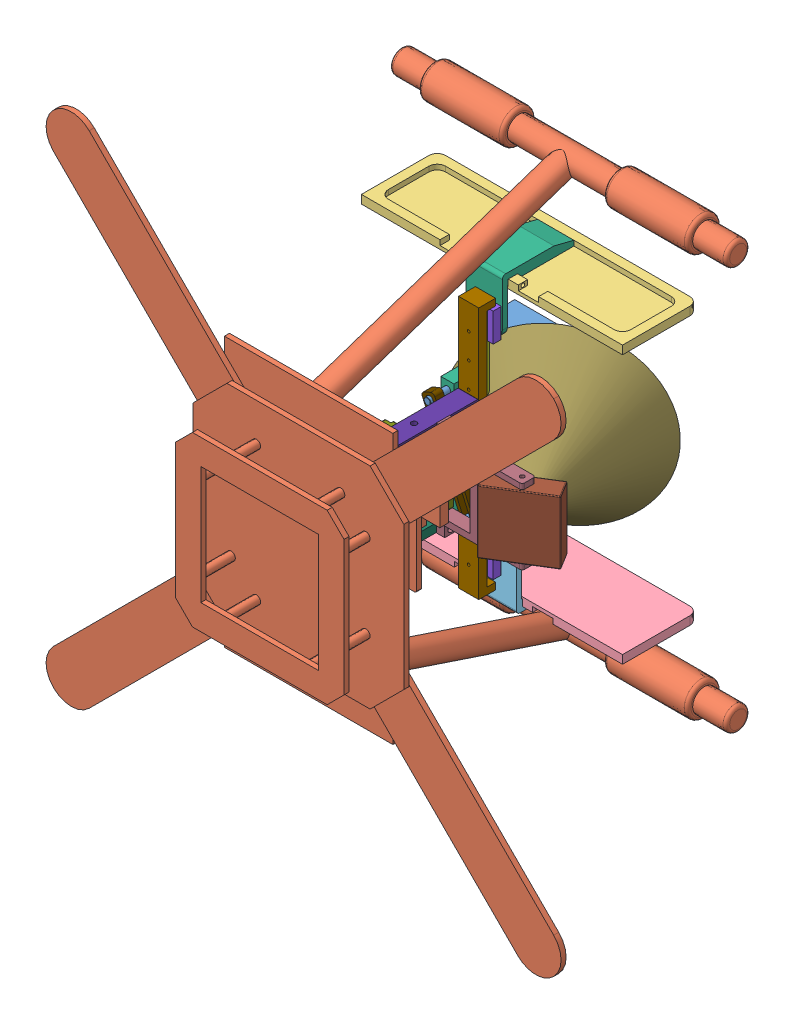
SolidWorks assembly 无人机抓取包裹, configuration 默认. Lengths in mm.
Overall size (305.77 305.77 197.93).
22 component instances, 20 part files, 59 mates.
Components (placement in the parent):
- 包裹-2: 包裹 [默认] at origin size (60 60 30)
- 无人机吊舱-2: 无人机吊舱 [默认] at (2.6457 0 120) size (305.77 305.77 194)
- 机械手-夹持板1-1: 机械手-夹持板1 [默认] at (0 77.0633 21) x (1 0 0) z (0 1 0) size (155 45 5)
- 机械手-夹持板2-2: 机械手-夹持板2 [默认] at (0 -77.0633 21) x (-1 0 0) z (0 -1 0) size (155 45 5)
- 导轨安装板-右侧-1: 导轨安装板-右侧 [默认] at (2.6457 -72.0633 46.5) x (0 1 0) z (0 0 -1) size (65 21.5 57.5)
- 导轨安装板-左侧-2: 导轨安装板-左侧 [默认] at (2.6457 72.0633 46.5) x (0 -1 0) z (0 0 -1) size (65 21.5 57.5)
- 导轨-1: 导轨 [默认] at (2.6457 0 55) x (0 -1 0) z (0 0 -1) size (140 5 4.8)
- 滑块-1: 滑块 [默认] at (2.6457 -52.0633 48.95) x (0 0 -1) z (0 -1 0) size (4.9 12 17)
- 滑块-2: 滑块 [默认] at (2.6457 69.0633 48.95) x (0 0 -1) z (0 -1 0) size (4.9 12 17)
- 导轨固定底板-1: 导轨固定底板 [默认] at (2.6457 0 60) x (0 -1 0) z (0 0 -1) size (150 12 10)
- 舵机转轴-2: 舵机转轴 [默认] at (2.6457 0 64) x (0.914342 0.404943 0) z (0 0 1) size (12 12 8.1)
- 摄像头-1: 摄像头 [默认] at (58.4666 0 85.8925) x (-0.850871 0 0.525374) z (-0.525374 0 -0.850871) size (36 37.5 17.5)
- 摄像头视角-1: 摄像头视角 [默认] at (49.5353 0 71.4277) x (0.277059 0.945502 -0.171071) z (0.8045 -0.325618 -0.496742) size (102.75 60 102.75)
- 摄像头固定支架-1: 摄像头固定支架 [默认] at (33.9457 0 85) x (0 1 0) z (0 0 -1) size (56.5 51 8)
- GB_FASTENER_SCREWS_SCHS M3X20-20-N-1: GB_FASTENER_SCREWS_SCHS M3X20-20-N [GB_FASTENER_SCREWS_SCHS M3X20-20-N] at (2.6457 0 63) x (0 0 1) z (-0.433867 0.900977 0) size (22.01 5.5 5.5)
- 连接板-1-1: 连接板-1 [默认] at (2.6457 -25.575 90) x (0 1 0) z (0 0 1) size (11 11.6 60)
- 单轴PWM舵机-1: 单轴PWM舵机 [默认] at (12.6457 0 78.1) x (-1 0 0) z (0 -1 0) size (57.5 45 20)
- 连接板-2-2: 连接板-2 [默认] at (2.6457 25.575 90) x (0 -1 0) z (0 0 1) size (11 11.6 60)
- 转动连杆-1: 转动连杆 [默认] at (2.6457 0 67) x (-0.914342 -0.404943 0) z (0 0 1) size (16 62.2 9)
- GB_FASTENER_SCREWS_HSHCS M4X25-N-1: GB_FASTENER_SCREWS_HSHCS M4X25-N [GB_FASTENER_SCREWS_HSHCS M4X25-N] at (13.7457 -25.0633 44.5) x (0 0 1) z (-0.946713 -0.322079 0) size (29 7 7)
- GB_FASTENER_SCREWS_HSHCS M4X25-N-2: GB_FASTENER_SCREWS_HSHCS M4X25-N [GB_FASTENER_SCREWS_HSHCS M4X25-N] at (-8.4543 25.0633 44.5) x (0 0 1) z (-0.907764 -0.419482 0) size (29 7 7)
- 舵机固定框-1: 舵机固定框 [默认] at (-7.3543 0 89.1) x (0 -1 0) z (0 0 1) size (46 54 5)
Mates (geometry in assembly coordinates):
- 宽度1: width: plane of assembly; plane of assembly; plane of assembly; plane of assembly; plane of 机械手-夹持板1-1 through (77.5 82.0633 43.5) normal (1 0 0); plane of 机械手-夹持板1-1 through (-77.5 82.0633 43.5) normal (-1 0 0); plane of 包裹-2 through (-30 -30 30) normal (-1 0 0); plane of 包裹-2 through (30 -30 30) normal (1 0 0)
- 宽度2: width: plane of assembly; plane of assembly; plane of assembly; plane of assembly; plane of 机械手-夹持板2-2 through (77.5 -82.0633 43.5) normal (1 0 0); plane of 机械手-夹持板2-2 through (-77.5 -82.0633 43.5) normal (-1 0 0); plane of 包裹-2 through (-30 -30 30) normal (-1 0 0); plane of 包裹-2 through (30 -30 30) normal (1 0 0)
- 平行1: parallel: plane of assembly; plane of assembly; plane of 包裹-2 through (30 -30 30) normal (0 -1 0); plane of 机械手-夹持板2-2 through (0 -77.0633 21) normal (0 1 0)
- 平行2: parallel: plane of assembly; plane of assembly; plane of 包裹-2 through (30 30 30) normal (0 1 0); plane of 机械手-夹持板1-1 through (0 77.0633 21) normal (0 -1 0)
- 重合1: coincident: plane of assembly; plane of assembly; plane of 机械手-夹持板2-2 through (0 -79.0633 21) normal (0 -1 0); plane of 导轨安装板-右侧-1 through (-2.3543 -79.0633 4) normal (0 1 0)
- 重合2: coincident: plane of assembly; plane of assembly; plane of 机械手-夹持板2-2 through (-77.5 -82.0633 43.5) normal (0 0 1); plane of 导轨安装板-右侧-1 through (2.6457 -72.0633 43.5) normal (0 0 -1)
- 重合3: coincident: plane of assembly; plane of assembly; plane of 机械手-夹持板1-1 through (0 79.0633 21) normal (0 1 0); plane of 导轨安装板-左侧-2 through (7.6457 79.0633 4) normal (0 -1 0)
- 重合4: coincident: plane of assembly; plane of assembly; plane of 机械手-夹持板1-1 through (77.5 82.0633 43.5) normal (0 0 1); plane of 导轨安装板-左侧-2 through (2.6457 72.0633 43.5) normal (0 0 -1)
- 宽度5: width: plane of assembly; plane of assembly; plane of assembly; plane of assembly; plane of 导轨-1 through (5.1457 -70 50.2) normal (1 0 0); plane of 导轨-1 through (0.1457 -70 50.2) normal (-1 0 0); plane of 滑块-1 through (5.1457 -52.0633 50.2) normal (-1 0 0); plane of 滑块-1 through (0.1457 -52.0633 51.4) normal (1 0 0)
- 重合5: coincident: plane of assembly; plane of assembly; plane of 导轨-1 through (2.6457 0 50.2) normal (0 0 -1); plane of 滑块-1 through (0.1457 -52.0633 50.2) normal (0 0 1)
- 宽度6: width: plane of assembly; plane of assembly; plane of assembly; plane of assembly; plane of 滑块-2 through (5.1457 69.0633 50.2) normal (-1 0 0); plane of 滑块-2 through (0.1457 69.0633 51.4) normal (1 0 0); plane of 导轨-1 through (5.1457 -70 50.2) normal (1 0 0); plane of 导轨-1 through (0.1457 -70 50.2) normal (-1 0 0)
- 重合6: coincident: plane of assembly; plane of assembly; plane of 导轨-1 through (2.6457 0 50.2) normal (0 0 -1); plane of 滑块-2 through (0.1457 69.0633 50.2) normal (0 0 1)
- 重合7: coincident: plane of assembly; plane of assembly; plane of 导轨安装板-左侧-2 through (2.6457 72.0633 46.5) normal (0 0 1); plane of 滑块-2 through (-3.3543 52.0633 46.5) normal (0 0 -1)
- 重合8: coincident: plane of assembly; plane of assembly; plane of 导轨安装板-左侧-2 through (7.6457 52.0633 43.5) normal (0 -1 0); plane of 滑块-2 through (2.6457 52.0633 48.95) normal (0 -1 0)
- 宽度7: width: plane of assembly; plane of assembly; plane of assembly; plane of assembly; plane of 导轨-1 through (5.1457 70 50.2) normal (0 1 0); plane of 导轨-1 through (5.1457 -70 50.2) normal (0 -1 0); plane of 包裹-2 through (30 -30 30) normal (0 -1 0); plane of 包裹-2 through (30 30 30) normal (0 1 0)
- 重合10: coincident: plane of assembly; plane of assembly; plane of 导轨安装板-右侧-1 through (2.6457 -72.0633 46.5) normal (0 0 1); plane of 滑块-1 through (-3.3543 -69.0633 46.5) normal (0 0 -1)
- 重合11: coincident: plane of assembly; plane of assembly; plane of 导轨-1 through (2.6457 0 55) normal (0 0 1); plane of 导轨固定底板-1 through (2.6457 0 55) normal (0 0 -1)
- 宽度8: width: plane of assembly; plane of assembly; plane of assembly; plane of assembly; plane of 导轨固定底板-1 through (-3.3543 71 50) normal (0 -1 0); plane of 导轨固定底板-1 through (-3.3543 -71 50) normal (0 1 0); plane of 导轨-1 through (5.1457 -70 50.2) normal (0 -1 0); plane of 导轨-1 through (5.1457 70 50.2) normal (0 1 0)
- 宽度9: width: plane of assembly; plane of assembly; plane of assembly; plane of assembly; plane of 导轨固定底板-1 through (-3.3543 -75 55) normal (-1 0 0); plane of 导轨固定底板-1 through (8.6457 -75 55) normal (1 0 0); plane of 导轨-1 through (5.1457 -70 50.2) normal (1 0 0); plane of 导轨-1 through (0.1457 -70 50.2) normal (-1 0 0)
- 同心6: concentric: cylinder of assembly; cylinder of assembly; cylinder of 导轨安装板-右侧-1 through (6.6457 -60.5633 43.5) axis (0 0 -1) radius 2.15; cylinder of 滑块-1 through (6.6457 -60.5633 46.5) axis (0 0 -1) radius 0.8
- 重合38: coincident: plane of assembly; plane of assembly; plane of 摄像头-1 through (49.5353 0 71.4277) normal (-0.525374 0 -0.850871); plane of 摄像头视角-1 through (48.2885 -4.2548 72.1975) normal (0.525374 0 0.850871)
- 同心9: concentric: circle of assembly; circle of assembly; circle of 摄像头-1; circle of 摄像头视角-1
- 宽度11: width: plane of assembly; plane of assembly; plane of assembly; plane of assembly; plane of 导轨固定底板-1 through (8.6457 75 55) normal (0 1 0); plane of 导轨固定底板-1 through (8.6457 -75 55) normal (0 -1 0); plane of 摄像头-1 through (37.1091 -18.75 85.5642) normal (0 -1 0); plane of 摄像头-1 through (37.1091 18.75 85.5642) normal (0 1 0)
- 宽度12: width: plane of assembly; plane of assembly; plane of assembly; plane of assembly; plane of 摄像头固定支架-1 through (34.4457 19 85) normal (0 -1 0); plane of 摄像头固定支架-1 through (59.4457 -19 85) normal (0 1 0); plane of 摄像头-1 through (37.1091 18.75 85.5642) normal (0 1 0); plane of 摄像头-1 through (37.1091 -18.75 85.5642) normal (0 -1 0)
- 同心10: concentric: cylinder of assembly; cylinder of assembly; cylinder of 摄像头-1 through (55.4457 -18.75 81) axis (0 -1 0) radius 0.8; cylinder of 摄像头固定支架-1 through (55.4457 -22.25 81) axis (0 -1 0) radius 1.25
- 同心12: concentric: cylinder of assembly; cylinder of assembly; cylinder of 舵机转轴-2 through (2.6457 0 72.1) axis (0 0 -1) radius 1.55; cylinder of GB_FASTENER_SCREWS_SCHS M3X20-20-N-1 through (2.6457 0 85) axis (0 0 -1) radius 1.5
- 重合45: coincident: plane of assembly; plane of assembly; plane of 舵机转轴-2 through (2.6457 0 65) normal (0 0 -1); plane of GB_FASTENER_SCREWS_SCHS M3X20-20-N-1 through (2.6457 0 65) normal (0 0 1)
- 宽度13: width: plane of assembly; plane of assembly; plane of assembly; plane of assembly; plane of 包裹-2 through (30 30 30) normal (0 1 0); plane of 包裹-2 through (30 -30 30) normal (0 -1 0); plane of 无人机吊舱-2 through (34.6457 -27.075 123) normal (0 -1 0); plane of 无人机吊舱-2 through (34.6457 27.075 123) normal (0 1 0)
- 重合48: coincident: plane of assembly; plane of assembly; plane of 无人机吊舱-2 through (2.6457 0 120) normal (0 0 -1); plane of 连接板-1-1 through (2.6457 -25.575 120) normal (0 0 1)
- 宽度19: width: plane of assembly; plane of assembly; plane of assembly; plane of assembly; plane of 无人机吊舱-2 through (-29.3543 -27.075 123) normal (-1 0 0); plane of 无人机吊舱-2 through (34.6457 -27.075 123) normal (1 0 0); plane of 连接板-1-1 through (8.4457 -23.075 120) normal (1 0 0); plane of 连接板-1-1 through (-3.1543 -23.075 120) normal (-1 0 0)
- 重合54: coincident: plane of assembly; plane of assembly; plane of 导轨固定底板-1 through (2.6457 0 60) normal (0 0 1); plane of 连接板-1-1 through (2.6457 -25.575 60) normal (0 0 -1)
- 距离1: distance = 1 mm: plane of assembly; plane of assembly; plane of 连接板-1-1 through (8.4457 -28.075 120) normal (0 -1 0); plane of 无人机吊舱-2 through (34.6457 -27.075 123) normal (0 -1 0)
- 重合62: coincident: plane of assembly; plane of assembly; plane of 连接板-1-1 through (-3.1543 -23.075 120) normal (-1 0 0); plane of 连接板-2-2 through (-3.1543 23.075 120) normal (-1 0 0)
- 重合63: coincident: plane of assembly; plane of assembly; plane of 无人机吊舱-2 through (2.6457 0 120) normal (0 0 -1); plane of 连接板-2-2 through (2.6457 25.575 120) normal (0 0 1)
- 距离2: distance = 1 mm: plane of assembly; plane of assembly; plane of 连接板-2-2 through (-3.1543 28.075 120) normal (0 1 0); plane of 无人机吊舱-2 through (34.6457 27.075 123) normal (0 1 0)
- 同心13: concentric: cylinder of assembly; cylinder of assembly; cylinder of GB_FASTENER_SCREWS_SCHS M3X20-20-N-1 through (2.6457 0 85) axis (0 0 -1) radius 1.5; cylinder of 单轴PWM舵机-1 through (2.6457 0 72.1) axis (0 0 1) radius 3
- 重合64: coincident: plane of assembly; plane of assembly; plane of 舵机转轴-2 through (2.6457 0 72.1) normal (0 0 1); plane of 单轴PWM舵机-1 through (2.6457 0 72.1) normal (0 0 -1)
- 宽度21: width: plane of assembly; plane of assembly; plane of assembly; plane of assembly; plane of 转动连杆-1 through (-2.7633 2.0885 72) normal (0.404943 -0.914342 0); plane of 转动连杆-1 through (0.5572 -5.4091 72) normal (-0.404943 0.914342 0); plane of 舵机转轴-2 through (7.9229 -2.0376 72.1) normal (0.404943 -0.914342 0); plane of 舵机转轴-2 through (4.6833 5.2771 72.1) normal (-0.404943 0.914342 0)
- 重合65: coincident: plane of assembly; plane of assembly; plane of 舵机转轴-2 through (2.6457 0 67) normal (0 0 1); plane of 转动连杆-1 through (2.6457 0 67) normal (0 0 -1)
- 宽度22: width: plane of assembly; plane of assembly; plane of assembly; plane of assembly; plane of 转动连杆-1 through (4.7343 5.4091 72) normal (-0.914342 -0.404943 0); plane of 转动连杆-1 through (-2.7633 2.0885 72) normal (0.914342 0.404943 0); plane of 舵机转轴-2 through (7.9229 -2.0376 72.1) normal (0.914342 0.404943 0); plane of 舵机转轴-2 through (0.6081 -5.2771 72.1) normal (-0.914342 -0.404943 0)
- 重合68: coincident: plane of assembly; plane of assembly; plane of 导轨安装板-右侧-1 through (13.7457 -25.0633 48.5) normal (0 0 -1); plane of GB_FASTENER_SCREWS_HSHCS M4X25-N-1 through (13.7457 -25.0633 48.5) normal (0 0 1)
- 距离3: distance = 3 mm: plane of assembly; plane of assembly; plane of 导轨固定底板-1 through (2.6457 0 60) normal (0 0 1); plane of GB_FASTENER_SCREWS_SCHS M3X20-20-N-1 through (2.6457 0 63) normal (0 0 -1)
- 同心17: concentric: cylinder of assembly; cylinder of assembly; cylinder of 导轨安装板-右侧-1 through (13.7457 -25.0633 48.5) axis (0 0 -1) radius 1.65; cylinder of GB_FASTENER_SCREWS_HSHCS M4X25-N-1 through (13.7457 -25.0633 73.5) axis (0 0 -1) radius 2
- 同心18: concentric: cylinder of assembly; cylinder of assembly; cylinder of 导轨安装板-左侧-2 through (-8.4543 25.0633 48.5) axis (0 0 -1) radius 1.65; cylinder of GB_FASTENER_SCREWS_HSHCS M4X25-N-2 through (-8.4543 25.0633 73.5) axis (0 0 -1) radius 2
- 重合69: coincident: plane of assembly; plane of assembly; plane of 导轨安装板-左侧-2 through (-8.4543 25.0633 48.5) normal (0 0 -1); plane of GB_FASTENER_SCREWS_HSHCS M4X25-N-2 through (-8.4543 25.0633 48.5) normal (0 0 1)
- 宽度24: width: plane of assembly; plane of assembly; plane of assembly; plane of assembly; plane of 导轨固定底板-1 through (-3.3543 -75 55) normal (-1 0 0); plane of 导轨固定底板-1 through (8.6457 -75 55) normal (1 0 0); plane of 连接板-2-2 through (8.4457 23.075 120) normal (1 0 0); plane of 连接板-2-2 through (-3.1543 23.075 120) normal (-1 0 0)
- 重合70: coincident: plane of assembly; plane of assembly; plane of 摄像头固定支架-1 through (8.4457 22.25 77) normal (-1 0 0); plane of 连接板-1-1 through (8.4457 -23.075 120) normal (1 0 0)
- 距离4: distance = 25 mm: plane of assembly; plane of assembly; plane of 摄像头固定支架-1 through (33.9457 0 85) normal (0 0 1); plane of 导轨固定底板-1 through (2.6457 0 60) normal (0 0 1)
- 宽度25: width: plane of assembly; plane of assembly; plane of assembly; plane of assembly; plane of 舵机固定框-1 through (-34.3543 15.5 94.1) normal (0 1 0); plane of 舵机固定框-1 through (-34.3543 -15.5 94.1) normal (0 -1 0); plane of 单轴PWM舵机-1 through (12.6457 -10 78.1) normal (0 -1 0); plane of 单轴PWM舵机-1 through (12.6457 10 78.1) normal (0 1 0)
- 宽度26: width: plane of assembly; plane of assembly; plane of assembly; plane of assembly; plane of 舵机固定框-1 through (-34.3543 -15.5 94.1) normal (-1 0 0); plane of 舵机固定框-1 through (19.6457 -15.5 94.1) normal (1 0 0); plane of 单轴PWM舵机-1 through (12.6457 -10 78.1) normal (1 0 0); plane of 单轴PWM舵机-1 through (-27.3543 -10 78.1) normal (-1 0 0)
- 重合71: coincident: plane of assembly; plane of assembly; plane of 单轴PWM舵机-1 through (12.6457 0 89.1) normal (0 0 1); plane of 舵机固定框-1 through (-7.3543 0 89.1) normal (0 0 -1)
- 同心21: concentric: cylinder of assembly; cylinder of assembly; cylinder of 导轨固定底板-1 through (2.6457 0 60) axis (0 0 1) radius 0.8; cylinder of 舵机转轴-2 through (2.6457 0 67) axis (0 0 -1) radius 6
- 平行3: parallel: plane of assembly; plane of assembly; plane of 连接板-1-1 through (8.4457 -28.075 120) normal (0 -1 0); plane of 单轴PWM舵机-1 through (12.6457 -10 78.1) normal (0 -1 0)
- 槽口1: slot: cylinder of GB_FASTENER_SCREWS_HSHCS M4X25-N-2 through (-8.4543 25.0633 73.5) axis (0 0 -1) radius 2; plane of 转动连杆-1 through (-6.5244 26.015 67) normal (-0.914342 -0.404943 0); cylinder of 转动连杆-1 through (-8.4902 25.1444 67) axis (0 0 1) radius 2.15; cylinder of GB_FASTENER_SCREWS_HSHCS M4X25-N-1; plane of 转动连杆-1; cylinder of 转动连杆-1
- 槽口2: slot: cylinder of GB_FASTENER_SCREWS_HSHCS M4X25-N-1 through (13.7457 -25.0633 73.5) axis (0 0 -1) radius 2; plane of 转动连杆-1 through (11.8158 -26.015 67) normal (0.914342 0.404943 0); cylinder of 转动连杆-1 through (13.7817 -25.1444 67) axis (0 0 1) radius 2.15
- 同心22: concentric: cylinder of assembly; cylinder of assembly; cylinder of 导轨安装板-左侧-2 through (6.6457 60.5633 43.5) axis (0 0 -1) radius 2.15; cylinder of 滑块-2 through (6.6457 60.5633 46.5) axis (0 0 -1) radius 0.8
- 宽度27: width: plane of assembly; plane of assembly; plane of assembly; plane of assembly; plane of 机械手-夹持板1-1 through (15.6457 79.0633 43.5) normal (1 0 0); plane of 机械手-夹持板1-1 through (-18.8543 65.8629 43.5) normal (-1 0 0); plane of 导轨安装板-左侧-2 through (-12.3543 72.0633 46.5) normal (-1 0 0); plane of 导轨安装板-左侧-2 through (9.1457 52.0633 36.5) normal (1 0 0)
- 重合72: coincident: plane of assembly; plane of assembly; plane of 机械手-夹持板1-1 through (77.5 82.0633 43.5) normal (1 0 0); plane of 机械手-夹持板2-2 through (77.5 -82.0633 43.5) normal (1 0 0)
- 距离5: distance = 120 mm: plane of assembly; plane of assembly; plane of 无人机吊舱-2 through (2.6457 0 120) normal (0 0 -1); plane of 包裹-2 through (0 0 0) normal (0 0 -1)
